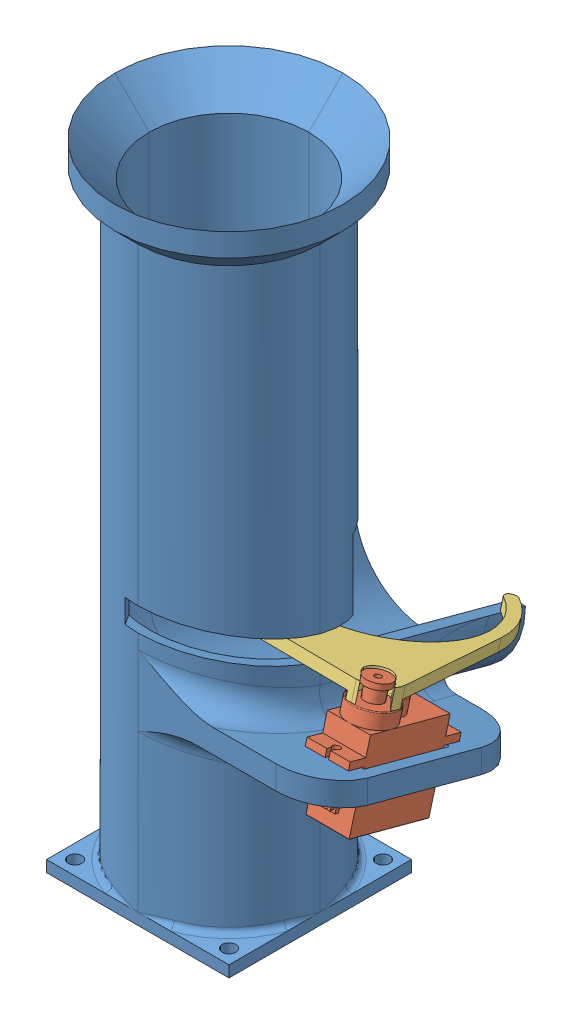
SolidWorks assembly ReloaderV2, configuration Default. Lengths in mm.
Overall size (96.73 176.96 88.9).
3 component instances, 3 part files, 5 mates.
Components (placement in the parent):
- BallTowerV2-1: BallTowerV2 [Default] at (3.5017 164.1907 113.2916) size (82.99 176.96 88.9)
- ReloaderServo-1: ReloaderServo [Default] at (44.7767 33.907 113.047) x (0 -0.258819 -0.965926) z (0 0.965926 -0.258819) size (32 12 32)
- GateV2-1: GateV2 [Default] at (44.7767 51.8757 113.9264) x (-0.663461 -0.193651 -0.722716) z (0.748211 -0.171716 -0.640854) size (54.73 5.17 63.84)
Mates (geometry in assembly coordinates):
- Coincident1: coincident anti-aligned: plane of BallTowerV2-1 through (60.6517 45.4372 138.6916) normal (0 0.965926 -0.258819); plane of Servo-1 through (50.7767 34.6949 98.6009) normal (0 -0.965926 0.258819)
- Concentric1: concentric anti-aligned: cylinder of BallTowerV2-1 through (44.7767 17.278 131.7378) axis (0 0.965926 -0.258819) radius 1; cylinder of Servo-1 through (44.7767 -1.7466 136.8355) axis (0 -0.965926 0.258819) radius 1
- Concentric2: concentric: cylinder of BallTowerV2-1 through (44.7767 10.1604 105.1749) axis (0 0.965926 -0.258819) radius 1; cylinder of Servo-1 through (44.7767 -8.8641 110.2725) axis (0 -0.965926 0.258819) radius 1
- Concentric6: concentric anti-aligned: cylinder of Servo-1 through (44.7767 53.6831 113.4421) axis (0 0.965926 -0.258819) radius 3.5; cylinder of GateV2-1 through (44.7767 68.1481 109.5662) axis (0 -0.965926 0.258819) radius 3.5
- Coincident3: coincident anti-aligned: plane of Servo-1 through (44.7767 55.132 113.0538) normal (0 0.965926 -0.258819); plane of GateV2-1 through (44.7767 55.132 113.0538) normal (0 -0.965926 0.258819)
